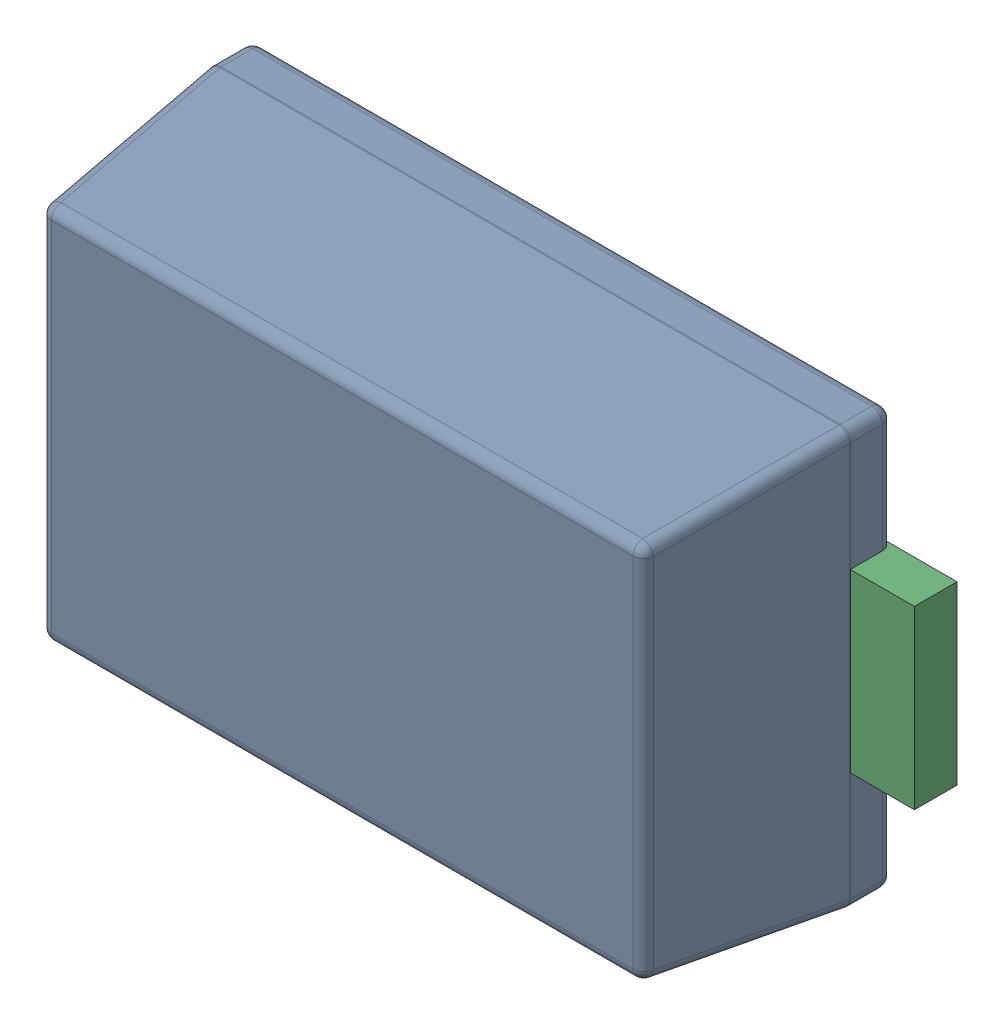
SolidWorks assembly 809534704, configuration Default. Lengths in mm.
Overall size (3.6 1.96 1.08).
4 component instances, 2 part files, 0 mates.
Components (placement in the parent):
- Body_3-1: Body_3 [Default] at (-1.5 -0.975 0) size (3.01 1.96 1.08)
  - Open_CASCADE_STEP_translator_6.8_1.1.1_2-1: Open_CASCADE_STEP_translator_6.8_1.1.1_2 [Default] at origin size (3.01 1.96 1.08)
- lead_2-1: lead_2 [Default] at (-1.8 -0.4125 0) size (0.68 0.82 0.2)
- lead_2-2: lead_2 [Default] at (1.8 0.4125 0) x (-1 0 0) z (0 0 1) size (0.68 0.82 0.2)
